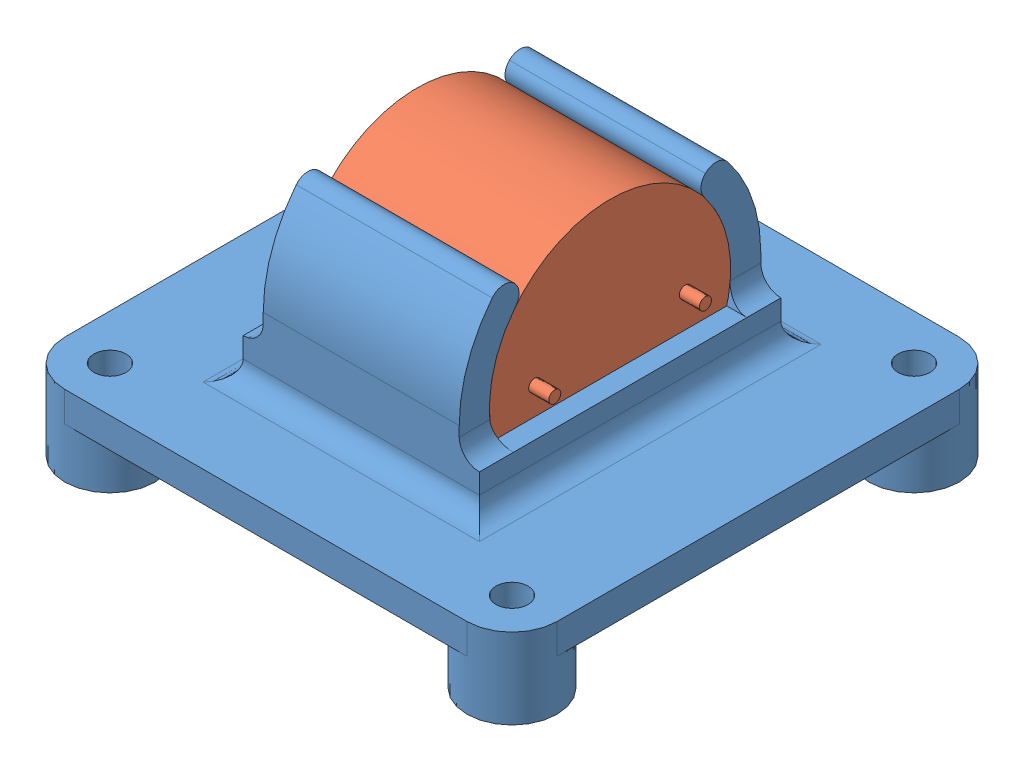
SolidWorks assembly Assem4, configuration Default. Lengths in mm.
Overall size (24.5 13.71 24.5).
2 component instances, 2 part files, 2 mates.
Components (placement in the parent):
- buzzer-mount-1: buzzer-mount [Default] at origin size (24.5 12.46 24.5)
- buzzer-1: buzzer [Default] at (4.875 7.5 0) x (0 -0.035809 0.999359) z (0 -0.999359 -0.035809) size (12 10.6 12)
Mates (geometry in assembly coordinates):
- Concentric1: concentric anti-aligned: cylinder of buzzer-mount-1 through (4.875 7.5 0) axis (-1 0 0) radius 6; cylinder of buzzer-1 through (-4.725 7.5 0) axis (1 0 0) radius 6
- Coincident1: coincident anti-aligned: plane of buzzer-mount-1 through (4.875 6 -7.5) normal (-1 0 0); plane of buzzer-1 through (4.875 7.5 0) normal (1 0 0)
